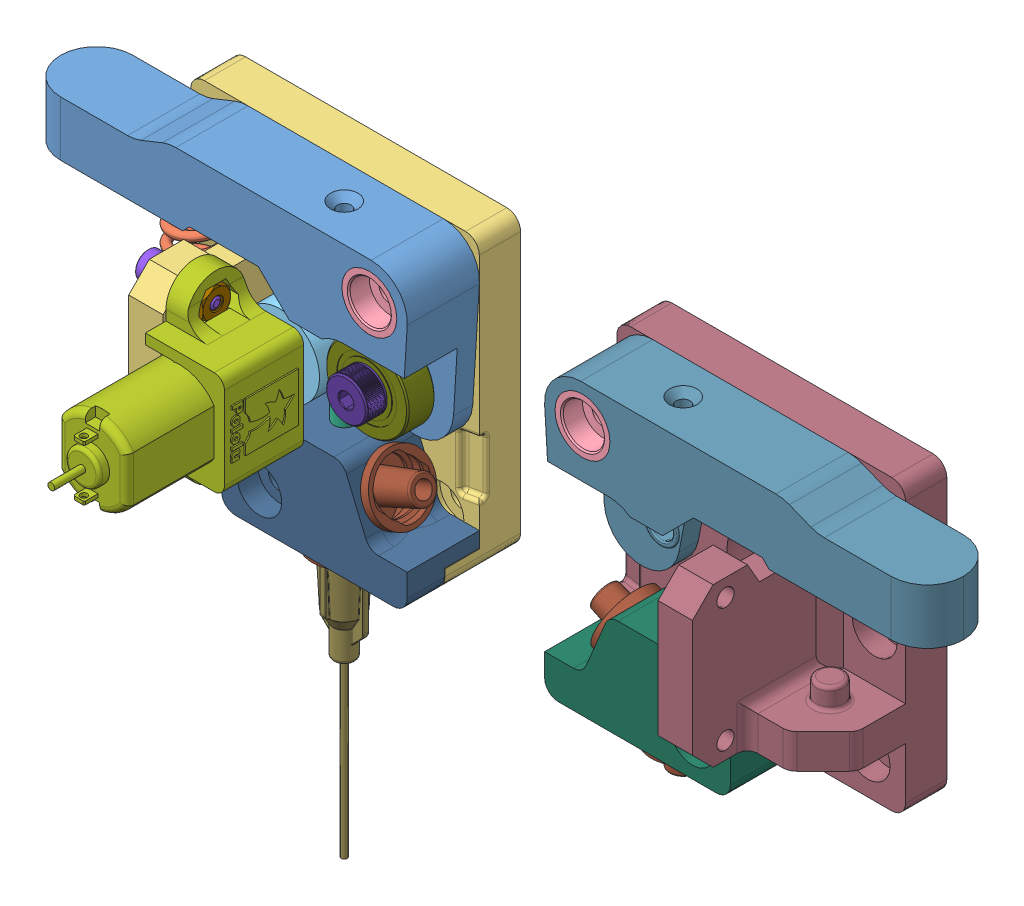
SolidWorks assembly Experimental Extruder Dual Extruder, configuration Default. Lengths in mm.
Overall size (131.31 82.59 47.28).
22 component instances, 17 part files, 54 mates.
Components (placement in the parent):
- ExtruderCR10 lever mirrored-1: ExtruderCR10 lever mirrored [Default] at (-21 -21 2) size (55.67 26.5 10.5)
- ExtruderCR10 spring-1: ExtruderCR10 spring [Default] at (-21 -21 1.5) size (8.03 21.41 8.04)
- Extruder custom base mirrored-1: Extruder custom base mirrored [Default] at origin size (42 42 26)
- ExtruderCR10 bushing-1: ExtruderCR10 bushing [Default] at (-21 -21 2) size (8 8 10.5)
- SLA Printed Driver-1: SLA Printed Driver [Default] at (0 0 -17.7668) size (11.5 11.5 6)
- 52335K910 TUBING MADE WITH PTFE cut to size-1: 52335K910 TUBING MADE WITH PTFE cut to size [52335K91] at (6.35 -9.5 11) x (0 1 0) z (0.546944 0 -0.837169) size (15 3 3)
- micro-metal-gearmotor-extended-with-1086-bracket (1)-1: micro-metal-gearmotor-extended-with-1086-bracket (1) [Default] at (0 0 26.27) x (0 0 -1) z (0 -1 0) size (39.3 11.72 26.5)
- 91290A015_BLACK-OXIDE CLASS 12.9 SOCKET HEAD CAP SCREW-1: 91290A015_BLACK-OXIDE CLASS 12.9 SOCKET HEAD CAP SCREW [91290A015] at (-2 -9 21.2) x (0 -0.941673 -0.336529) z (1 0 0) size (3.8 3.8 10.11)
- 91290A015_BLACK-OXIDE CLASS 12.9 SOCKET HEAD CAP SCREW-2: 91290A015_BLACK-OXIDE CLASS 12.9 SOCKET HEAD CAP SCREW [91290A015] at (-2 9 21.2) x (0 -0.660306 0.750996) z (1 0 0) size (3.8 3.8 10.11)
- 91828A111_TYPE 18-8 STAINLESS STEEL HEX NUT-1: 91828A111_TYPE 18-8 STAINLESS STEEL HEX NUT [91828A111] at (-2.8 9 21.2) x (0 0 1) z (-1 0 0) size (4 4.62 1.83)
- SLA Printed Manifold-1: SLA Printed Manifold [Default] at origin size (27 14.5 10.5)
- Luer male print with manifold-2: Luer male print with manifold [Default] at (17.8808 -9.5965 11) x (0.923028 0.384734 0) z (0 0 1) size (8.55 9.27 9.27)
- Luer male print with manifold-3: Luer male print with manifold [Default] at (6.35 -25.5471 11) x (0 -1 0) z (0 0 1) size (8.55 9.27 9.27)
- Syringe Needle, With Luer-2: Syringe Needle, With Luer [Yellow_20Gauge] at (6.35 -36.1851 11) x (0 1 0) z (0 0 1) size (43.15 7.7 8.15)
- MirrorExtruder custom base-2: MirrorExtruder custom base [Default] at (62 0 0) x (-1 0 0) z (0 0 -1) size (42 42 26)
- MirrorExtruderCR10 lever-2: MirrorExtruderCR10 lever [Default] at (83 -21 2) x (-1 0 0) z (0 0 -1) size (55.67 26.5 10.5)
- ExtruderCR10 bushing-2: ExtruderCR10 bushing [Default] at (10 -21 2) size (8 8 10.5)
- Luer male print with manifold-5: Luer male print with manifold [Default] at (44.1192 -9.5965 11) x (-0.923028 0.384734 0) z (0 0 1) size (8.55 9.27 9.27)
- MirrorPart21-2: MirrorPart21 [Default] at (62 0 0) x (-1 0 0) z (0 0 -1) size (27 14.5 10.5)
- Luer male print with manifold-6: Luer male print with manifold [Default] at (55.65 -25.5471 11) x (0 -1 0) z (0 0 -1) size (8.55 9.27 9.27)
- 7804K102_STAINLESS STEEL BALL BEARING-1: 7804K102_STAINLESS STEEL BALL BEARING [7804K102] at (11.6075 1 11) x (0.999251 0.038691 0) z (0 0 1) size (12 12 4)
- 91273A351_SAME-SIZE THREAD 18-8 SS SHOULDER SCREW-1: 91273A351_SAME-SIZE THREAD 18-8 SS SHOULDER SCREW [91273A351] at (11.6075 1 16) x (0.991631 -0.129104 0) z (0 0 1) size (6 6 11.85)
Mates (geometry in assembly coordinates):
- Concentric1: concentric anti-aligned: cylinder of ExtruderCR10 lever-1 through (15.5 15.5 6) axis (0 0 1) radius 2.5; cylinder of ExtruderCR10 bushing-1 through (15.5 15.5 6) axis (0 0 -1) radius 1.6
- Coincident1: coincident aligned: plane of ExtruderCR10 lever-1 through (14.552 0 6) normal (0 0 -1); plane of ExtruderCR10 bushing-1 through (17.1 15.5 6) normal (0 0 -1)
- Concentric2: concentric anti-aligned: cylinder of Extruder custom base-1 through (15.5 15.5 6) axis (0 0 1) radius 1.7; cylinder of ExtruderCR10 bushing-1 through (15.5 15.5 6) axis (0 0 -1) radius 1.6
- Coincident2: coincident anti-aligned: plane of ExtruderCR10 lever-1 through (14.552 0 6) normal (0 0 -1); plane of Extruder custom base-1 through (0 0 6) normal (0 0 1)
- Concentric3: concentric aligned: cylinder of ExtruderCR10 idler-1 through (11.6075 1 12.8172) axis (0 0 1) radius 1.6; cylinder of ExtruderCR10 lever-1 through (11.6075 1 6) axis (0 0 1) radius 1.75
- Coincident3: coincident anti-aligned: plane of ExtruderCR10 idler-1 through (13.2075 1 9) normal (0 0 -1); plane of ExtruderCR10 lever-1 through (11.6075 1 9) normal (0 0 1)
- Concentric4: concentric anti-aligned: cylinder of ExtruderCR10 lever-1 through (11.6075 1 6) axis (0 0 1) radius 1.75; cylinder of ExtruderCR10 M3-1 through (11.6075 1 7) axis (0 0 -1) radius 1.5
- Coincident4: coincident anti-aligned: plane of ExtruderCR10 idler-1 through (18.1075 1 13) normal (0 0 1); plane of ExtruderCR10 M3-1 through (13.1075 1 13) normal (0 0 -1)
- Coincident5: coincident aligned: plane of ExtruderCR10 lever-1 through (21.3467 21 16.5) normal (0 1 0); plane of Extruder custom base-1 through (-21 21 6) normal (0 1 0)
- Concentric5: concentric anti-aligned: cylinder of Extruder custom base-1 through (0 0 0) axis (0 0 1) radius 5; cylinder of 20d-metal-gearmotor-25-31-with-extended-motor-shaft-1 through (0 0 19.5) axis (0 0 -1) radius 2
- Parallel1: parallel anti-aligned: plane of 20d-metal-gearmotor-25-31-with-extended-motor-shaft-1 through (23.8942 -21.0034 65.0067) normal (-1 0 0)
- Distance1: distance = 1.5 mm aligned: plane of 20d-metal-gearmotor-25-31-with-extended-motor-shaft-1 through (0 0 1.5) normal (0 0 -1); plane of Extruder custom base-1 through (0 0 0) normal (0 0 -1)
- Concentric6: concentric aligned: cylinder of 20d-metal-gearmotor-25-31-with-extended-motor-shaft-1 through (0 0 19.5) axis (0 0 -1) radius 2; cylinder of Part1-1 through (0 0 14) axis (0 0 -1) radius 2
- Width1: width anti-aligned: plane of Part1-1 through (0 0 8) normal (0 0 -1); plane of ExtruderCR10 idler-1 through (0 0 14) normal (0 0 1); plane of Part1-1 through (13.2075 1 9) normal (0 0 -1); plane of ExtruderCR10 idler-1 through (18.1075 1 13) normal (0 0 1)
- Coincident9: coincident aligned: plane of ExtruderCR10 base-1 through (-21 -21 4) normal (-1 0 0); plane of Extruder custom base-1 through (-21 -21 6) normal (-1 0 0)
- Coincident10: coincident aligned: plane of ExtruderCR10 base-1 through (-21 21 4) normal (0 1 0); plane of Extruder custom base-1 through (-21 21 6) normal (0 1 0)
- Coincident11: coincident aligned: plane of ExtruderCR10 base-1 through (-21 -21 0) normal (0 0 -1); plane of Extruder custom base-1 through (0 0 0) normal (0 0 -1)
- Concentric7: concentric aligned: cylinder of ExtruderCR10 spring-1 through (-15 -6.4 11) axis (0 -1 0) radius 3; cylinder of Extruder custom base-1 through (-15 -3.5 11) axis (0 -1 0) radius 2
- Coincident12: coincident anti-aligned: plane of ExtruderCR10 spring-1 through (-21 -6.5 11) normal (0 -1 0); plane of Extruder custom base-1 through (-21 -6.5 18) normal (0 1 0)
- Coincident13: coincident aligned: plane of Extruder custom base-1 through (0 0 0) normal (0 0 -1); plane of 94510A360_BRASS SCREW-TO-EXPAND INSERTS FOR PLASTICS-1 through (-0.5 -16 0) normal (0 0 -1)
- Parallel2: parallel anti-aligned: plane of 94510A360_BRASS SCREW-TO-EXPAND INSERTS FOR PLASTICS-1 through (-0.5 -16 0) normal (0 -1 0)
- Concentric8: concentric aligned: cylinder of Extruder custom base-1 through (-0.5 -16 18.001) axis (0 0 -1) radius 2.05; cylinder of 94510A360_BRASS SCREW-TO-EXPAND INSERTS FOR PLASTICS-1 through (-0.5 -16 0.5) axis (0 0 -1) radius 2.4
- Coincident15: coincident aligned: plane of 94510A240_BRASS SCREW-TO-EXPAND INSERTS-1 through (-3.2686 -16 0) normal (0 0 -1); plane of Extruder custom base-1 through (0 0 0) normal (0 0 -1)
- Concentric9: concentric aligned: cylinder of 94510A240_BRASS SCREW-TO-EXPAND INSERTS-1 through (-0.5 -16 0.6096) axis (0 0 -1) radius 2.7686; cylinder of Extruder custom base-1 through (-0.5 -16 18.001) axis (0 0 -1) radius 2.05
- Parallel3: parallel aligned: plane of 94510A240_BRASS SCREW-TO-EXPAND INSERTS-1 through (-0.5 -16 0) normal (0 1 0)
- Concentric14: concentric anti-aligned: cylinder of Part1-1 through (0 0 14) axis (0 0 -1) radius 2; cylinder of micro-metal-gearmotor-extended-with-1086-bracket (1)-1 through (0 0 7.27) axis (0 0 1) radius 1.5
- Parallel7: parallel anti-aligned: plane of Extruder custom base-1 through (-6 -11.5 26) normal (1 0 0); plane of micro-metal-gearmotor-extended-with-1086-bracket (1)-1 through (-5 -3.3166 41.27) normal (-1 0 0)
- Distance2: distance = 0 mm aligned: plane of micro-metal-gearmotor-extended-with-1086-bracket (1)-1 through (0 0 8) normal (0 0 -1); plane of Part1-1 through (0 0 8) normal (0 0 -1)
- Concentric15: concentric aligned: cylinder of Extruder custom base-1 through (-21.001 -9 21.2) axis (1 0 0) radius 1.25; cylinder of 91290A015_BLACK-OXIDE CLASS 12.9 SOCKET HEAD CAP SCREW-1 through (-12 -9 21.2) axis (1 0 0) radius 1.9
- Concentric16: concentric aligned: cylinder of Extruder custom base-1 through (-21.001 9 21.2) axis (1 0 0) radius 1.25; cylinder of 91290A015_BLACK-OXIDE CLASS 12.9 SOCKET HEAD CAP SCREW-2 through (-12 9 21.2) axis (1 0 0) radius 1.9
- Coincident28: coincident anti-aligned: plane of Extruder custom base-1 through (-10 -11.5 26) normal (-1 0 0); plane of 91290A015_BLACK-OXIDE CLASS 12.9 SOCKET HEAD CAP SCREW-2 through (-10 9 21.2) normal (1 0 0)
- Coincident29: coincident anti-aligned: plane of Extruder custom base-1 through (-10 -11.5 26) normal (-1 0 0); plane of 91290A015_BLACK-OXIDE CLASS 12.9 SOCKET HEAD CAP SCREW-1 through (-10 -9 21.2) normal (1 0 0)
- Coincident30: coincident anti-aligned: plane of micro-metal-gearmotor-extended-with-1086-bracket (1)-1 through (-3.6 8.1297 21.3196) normal (1 0 0); plane of 91828A111_TYPE 18-8 STAINLESS STEEL HEX NUT-1 through (-3.6 10.1547 19.2) normal (-1 0 0)
- Concentric17: concentric aligned: cylinder of Extruder custom base-1 through (-21.001 9 21.2) axis (1 0 0) radius 1.25; circle of 91828A111_TYPE 18-8 STAINLESS STEEL HEX NUT-1
- Parallel11: parallel aligned: plane of Syringe Needle, With Luer-2 through (6.35 -36.1851 11) normal (0 0 1)
- Parallel12: parallel aligned: plane of Luer male-1 through (6.35 -25.5471 11) normal (1 0 0)
- Coincident36: coincident anti-aligned: plane of Luer male-1 through (6.35 -17 11) normal (0 1 0); plane of 52335K910_METRIC EXTREME-TEMP TUBING MADE WITH PTFE-1 through (6.35 -17 11) normal (0 -1 0)
- Coincident37: coincident anti-aligned: plane of Luer male-1 through (10.3505 -18.4351 11) normal (0 -1 0); plane of Syringe Needle, With Luer-2 through (4.3 -18.4351 11) normal (0 1 0)
- Concentric22: concentric anti-aligned: cylinder of Luer male-1 through (6.35 -17 11) axis (0 1 0) radius 1.1811; cylinder of Syringe Needle, With Luer-2 through (6.35 -30.6851 11) axis (0 -1 0) radius 0.32
- Parallel13: parallel aligned: plane of Luer male-2 through (17.8808 -9.5965 11) normal (0 0 1)
- Concentric23: concentric aligned: cylinder of Part2-1 through (6.35 -6.5 11) axis (0 -1 0) radius 1.5; cylinder of 52335K910_METRIC EXTREME-TEMP TUBING MADE WITH PTFE-1 through (6.35 -2 11) axis (0 -1 0) radius 1.5
- Coincident38: coincident anti-aligned: plane of Part2-1 through (0 0 16.5) normal (0 0 1); plane of Part3-1 through (121.6474 -10.6831 16.5) normal (0 0 -1)
- Concentric24: concentric anti-aligned: cylinder of Part2-1 through (6.35 -6.5 11) axis (0 -1 0) radius 1.5; cylinder of Luer male-1 through (6.35 -17 11) axis (0 1 0) radius 1.1811
- Coincident39: coincident anti-aligned: plane of Part2-1 through (6.35 -17 11) normal (0 -1 0); plane of Luer male-1 through (6.35 -17 11) normal (0 1 0)
- Concentric25: concentric anti-aligned: cylinder of Luer male-2 through (9.9916 -12.8848 11) axis (-0.923028 -0.384734 0) radius 4.6355; cylinder of Part2-1 through (9.9916 -12.8848 11) axis (0.923028 0.384734 0) radius 4.6355
- Coincident40: coincident anti-aligned: plane of Part2-1 through (9.9916 -12.8848 11) normal (0.923028 0.384734 0); plane of Luer male-2 through (9.9916 -12.8848 11) normal (-0.923028 -0.384734 0)
- Concentric26: concentric anti-aligned: cylinder of ExtruderCR10 idler-1 through (11.6075 1 12.8172) axis (0 0 1) radius 1.6; cylinder of 92981A741_ALLOY STEEL SHOULDER SCREW-1 through (11.6075 1 3) axis (0 0 -1) radius 2
- Coincident41: coincident anti-aligned: plane of ExtruderCR10 idler-1 through (18.1075 1 13) normal (0 0 1); plane of 92981A741_ALLOY STEEL SHOULDER SCREW-1 through (11.6075 -2 11) normal (0 0 -1)
- Concentric27: concentric anti-aligned: cylinder of 92981A741_ALLOY STEEL SHOULDER SCREW-1 through (11.6075 1 3) axis (0 0 -1) radius 2; cylinder of 7804K102_STAINLESS STEEL BALL BEARING-1 through (11.6075 1 13) axis (0 0 1) radius 2
- Coincident42: coincident anti-aligned: plane of 92981A741_ALLOY STEEL SHOULDER SCREW-1 through (11.6075 -2 11) normal (0 0 -1); plane of 7804K102_STAINLESS STEEL BALL BEARING-1 through (11.4664 4.6456 13) normal (0 0 1)
- Concentric28: concentric anti-aligned: cylinder of 7804K102_STAINLESS STEEL BALL BEARING-1 through (11.6075 1 13) axis (0 0 1) radius 2; cylinder of 91273A351_SAME-SIZE THREAD 18-8 SS SHOULDER SCREW-1 through (11.6075 1 4.5) axis (0 0 -1) radius 2
- Concentric29: concentric anti-aligned: cylinder of ExtruderCR10 lever-1 through (11.6075 1 6) axis (0 0 1) radius 1.75; cylinder of 91273A351_SAME-SIZE THREAD 18-8 SS SHOULDER SCREW-1 through (11.6075 1 4.5) axis (0 0 -1) radius 2
- Coincident43: coincident anti-aligned: plane of ExtruderCR10 lever-1 through (11.6075 1 9) normal (0 0 1); plane of 7804K102_STAINLESS STEEL BALL BEARING-1 through (11.5224 3.1984 9) normal (0 0 -1)
- Coincident44: coincident anti-aligned: plane of 7804K102_STAINLESS STEEL BALL BEARING-1 through (11.4664 4.6456 13) normal (0 0 1); plane of 91273A351_SAME-SIZE THREAD 18-8 SS SHOULDER SCREW-1 through (11.2202 -1.9749 13) normal (0 0 -1)
